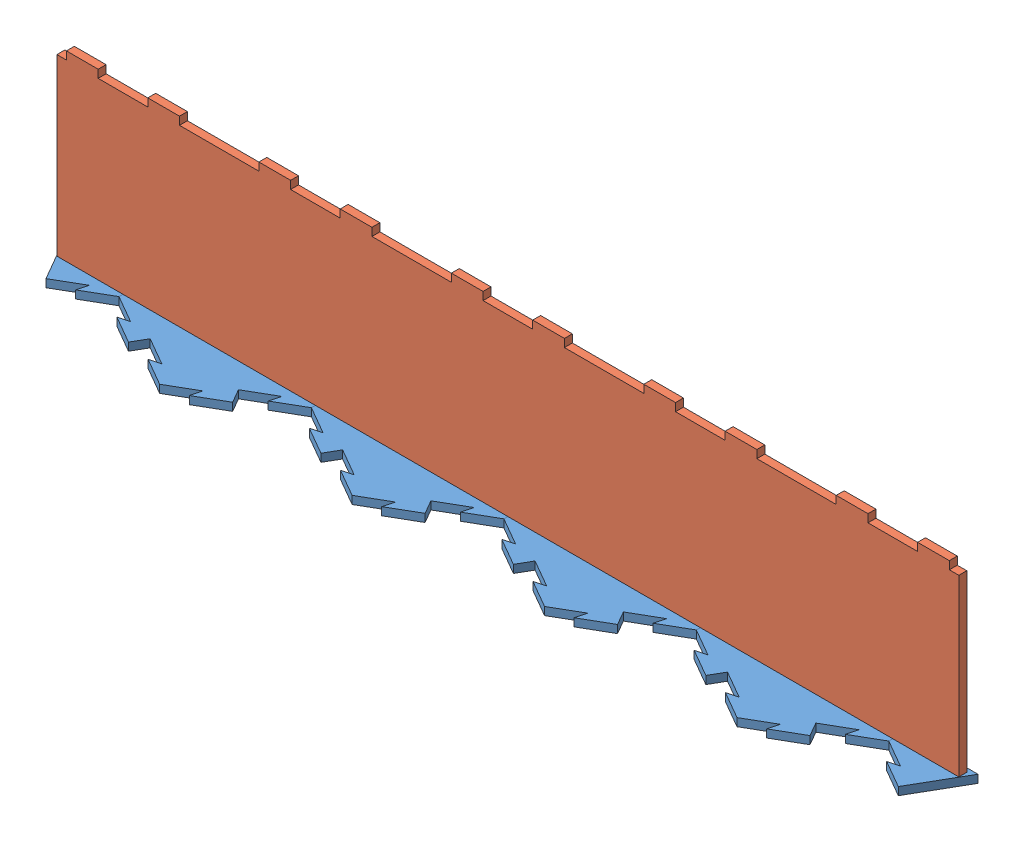
SolidWorks assembly Assem1, configuration Default. Lengths in mm.
Overall size (733.23 152.4 88.9).
2 component instances, 2 part files, 3 mates.
Components (placement in the parent):
- border-1: border [Default] at origin size (733.23 6.35 88.9)
- Wall_seg-1: Wall_seg [Default] at (230.969 69.85 -9.525) x (1 0 0) z (0 -1 0) size (721.64 6.35 152.4)
Mates (geometry in assembly coordinates):
- Coincident1: coincident: plane of border-1 through (584.1673 -6.35 -9.525) normal (-1 0 0); plane of Wall_seg-1 through (584.1673 -6.35 -9.525) normal (1 0 0)
- Coincident2: coincident: plane of border-1 through (558.7673 -6.35 -3.175) normal (0 0 -1); plane of Wall_seg-1 through (230.969 69.85 -3.175) normal (0 0 1)
- Coincident3: coincident aligned: plane of border-1 through (615.9173 -6.35 0) normal (0 -1 0); plane of Wall_seg-1 through (-129.8493 -6.35 -3.175) normal (0 -1 0)
